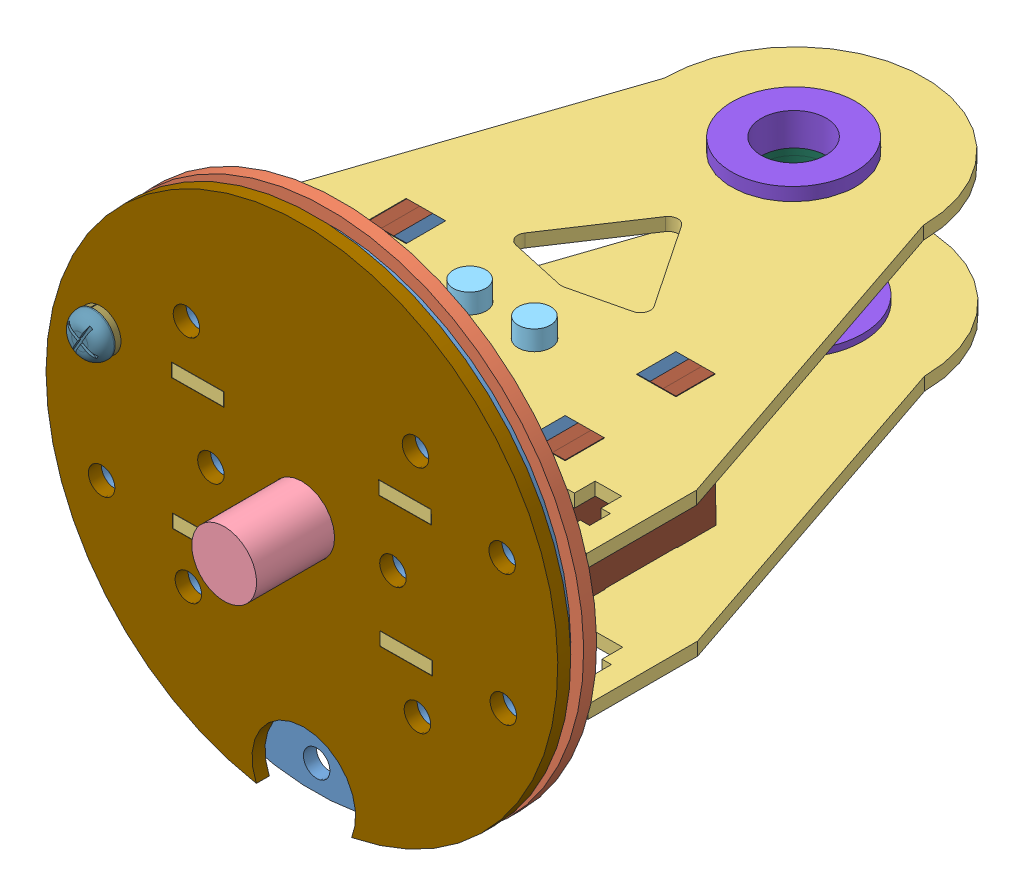
SolidWorks assembly j1, configuration 默认. Lengths in mm.
Overall size (79.65 78.96 105).
36 component instances, 15 part files, 29 mates.
Components (placement in the parent):
- 关节盘-中间层-1: 关节盘-中间层 [默认] at (6.907 71.2488 34.9133) x (0.999966 0.008302 0) z (0 0 1) size (75 75 2)
- 关节盘-两侧层-1: 关节盘-两侧层 [默认] at (6.907 71.2488 32.9133) x (0.999966 0.008302 0) z (0 0 1) size (79 78.31 2)
- 垂直板-1: 垂直板 [默认] at (6.79 60.1974 36.0435) x (0.999966 0.008302 0) z (-0.008302 0.999966 0) size (76.1 93 4.1)
- 垂直板-2: 垂直板 [默认] at (6.6231 80.2967 36.0435) x (0.999966 0.008302 0) z (-0.008302 0.999966 0) size (76.1 93 4.1)
- 螺栓M10-18-1: 螺栓M10-18 [默认] at (6.907 71.2488 32.9133) size (17.5 17.5 23.5)
- 光轴柱-1: 光轴柱 [默认] at (-62.2448 52.8493 0) x (0.350441 -0.936585 0) z (0 0 1) size (28.47 15.53 9.86)
  - M5光轴对线用-1: M5光轴对线用 [默认] at (21.8197 71.1318 7.9133) x (0.325138 0.891437 0.315635) z (-0.939462 0.342654 0) size (5 5 28)
  - 铜套5-7-10-1: 铜套5-7-10 [默认] at (13.3646 74.2157 7.9133) x (0.218976 0.600371 0.769158) z (-0.939462 0.342654 0) size (7 7 10)
  - 铜套5-7-4-1: 铜套5-7-4 [默认] at (17.1224 72.8451 7.9133) x (0.338822 0.928955 0.149138) z (-0.939462 0.342654 0) size (7 7 4)
  - 铜套5-7-4-2: 铜套5-7-4 [默认] at (3.97 77.6422 7.9133) x (0.197516 0.541533 -0.817147) z (-0.939462 0.342654 0) size (7 7 4)
- 法兰轴承10-19-5-金鑫莱-1_6-1: 法兰轴承10-19-5-金鑫莱-1_6 [默认] at (6.8319 80.2985 -37.0867) x (0.526763 0.004373 0.850001) z (-0.008302 0.999966 0) size (21 21 5)
- 法兰轴承10-19-5-金鑫莱-1_6-2: 法兰轴承10-19-5-金鑫莱-1_6 [默认] at (6.9822 62.1991 -37.0867) x (0.500266 0.004153 0.865862) z (0.008302 -0.999966 0) size (21 21 5)
- 关节盘-两侧层-m4孔-1: 关节盘-两侧层-m4孔 [默认] at (6.907 71.2488 36.9133) x (0.999966 0.008302 0) z (0 0 1) size (79 78.31 2)
- 线口板-2: 线口板 [默认] at (-86.2629 82.2299 14.3053) x (-0.036209 -0.999344 0) z (0 0 1) size (22.35 6.98 23.1)
  - 线口板-1: 线口板 [默认] at (-3.3196 112.811 -12.4421) x (0 0 1) z (0.044504 -0.999009 0) size (23.1 22.1 2)
  - 线口板-M4孔-1: 线口板-M4孔 [默认] at (-3.4086 114.809 -12.4421) x (0 0 1) z (0.044504 -0.999009 0) size (23.1 22.1 2)
  - 线口板-M4孔-2: 线口板-M4孔 [默认] at (-3.4976 116.807 -12.4421) x (0 0 1) z (0.044504 -0.999009 0) size (23.1 22.1 2)
- 线口板-3: 线口板 [默认] at (99.8818 83.7753 6.5212) x (0.052796 -0.998605 0) z (0 0 -1) size (22.35 6.98 23.1)
  - 线口板-1: 线口板 [默认] at (-3.3196 112.811 -12.4421) x (0 0 1) z (0.044504 -0.999009 0) size (23.1 22.1 2)
  - 线口板-M4孔-1: 线口板-M4孔 [默认] at (-3.4086 114.809 -12.4421) x (0 0 1) z (0.044504 -0.999009 0) size (23.1 22.1 2)
  - 线口板-M4孔-2: 线口板-M4孔 [默认] at (-3.4976 116.807 -12.4421) x (0 0 1) z (0.044504 -0.999009 0) size (23.1 22.1 2)
- 光轴柱-2: 光轴柱 [默认] at (-72.2445 52.7663 0) x (0.350441 -0.936585 0) z (0 0 1) size (28.47 15.53 9.86)
  - M5光轴对线用-1: M5光轴对线用 [默认] at (21.8197 71.1318 7.9133) x (0.325138 0.891437 0.315635) z (-0.939462 0.342654 0) size (5 5 28)
  - 铜套5-7-10-1: 铜套5-7-10 [默认] at (13.3646 74.2157 7.9133) x (0.218976 0.600371 0.769158) z (-0.939462 0.342654 0) size (7 7 10)
  - 铜套5-7-4-1: 铜套5-7-4 [默认] at (17.1224 72.8451 7.9133) x (0.338822 0.928955 0.149138) z (-0.939462 0.342654 0) size (7 7 4)
  - 铜套5-7-4-2: 铜套5-7-4 [默认] at (3.97 77.6422 7.9133) x (0.197516 0.541533 -0.817147) z (-0.939462 0.342654 0) size (7 7 4)
- M4螺栓螺母垫片16-1: M4螺栓螺母垫片16 [默认] at (-40.0759 -6.7925 45.0566) x (0.498996 -0.866604 0) z (0 0 1) size (8.9 8.9 18.35)
  - M4弹簧垫片-1-6.3-1: M4弹簧垫片-1-6.3 [默认] at (-68.1827 57.608 -5.1433) x (-0.994897 -0.100898 0) z (0 0 -1) size (6.3 6.3 1)
  - 螺母M4-1: 螺母M4 [默认] at (-68.1827 57.608 -16.1433) x (-0.994897 -0.100898 0) z (0 0 -1) size (7.74 6.73 3)
  - 螺栓M4-16-1: 螺栓M4-16 [默认] at (-68.1827 57.608 -5.1433) x (-0.50685 0.862034 0) z (0 0 -1) size (6.5 6.5 18.35)
- M10垫片16-1-1: M10垫片16-1 [默认] at (6.8485 78.2985 -37.0867) x (0.653384 0.005424 0.757007) z (-0.008302 0.999966 0) size (16 16 1)
- M10垫片16-1-2: M10垫片16-1 [默认] at (6.8568 77.2986 -37.0867) x (0.653384 0.005424 0.757007) z (-0.008302 0.999966 0) size (16 16 1)
- M10垫片16-1-3: M10垫片16-1 [默认] at (6.8651 76.2986 -37.0867) x (-0.117982 -0.000979 0.993015) z (-0.008302 0.999966 0) size (16 16 1)
- M10垫片16-1-4: M10垫片16-1 [默认] at (6.9739 63.1991 -37.0867) x (0.214974 0.001785 0.976618) z (-0.008302 0.999966 0) size (16 16 1)
- M10垫片16-1-5: M10垫片16-1 [默认] at (6.9656 64.199 -37.0867) x (0.336961 0.002797 0.941515) z (-0.008302 0.999966 0) size (16 16 1)
- M10垫片16-1-6: M10垫片16-1 [默认] at (6.9573 65.199 -37.0867) x (0.336961 0.002797 0.941515) z (-0.008302 0.999966 0) size (16 16 1)
Mates (geometry in assembly coordinates):
- 重合2: coincident aligned: circle of 关节盘-中间层-1; circle of 关节盘-两侧层-1
- 同心1: concentric aligned: cylinder of 关节盘-中间层-1 through (24.7308 53.7185 36.9133) axis (0 0 -1) radius 2.05; cylinder of 关节盘-两侧层-1 through (24.7308 53.7185 34.9133) axis (0 0 -1) radius 2.05
- 重合10: coincident aligned: circle of 关节盘-两侧层-1; circle of 垂直板-1
- 平行1: parallel anti-aligned: plane of 关节盘-两侧层-1 through (-4.9678 62.1499 34.9133) normal (0.008302 -0.999966 0); plane of 垂直板-1 through (6.9822 62.1991 -37.0867) normal (-0.008302 0.999966 0)
- 重合11: coincident aligned: circle of 关节盘-两侧层-1; circle of 垂直板-2
- 同心8: concentric aligned: circle of 关节盘-两侧层-1; circle of 螺栓M10-18-1
- 重合12: coincident aligned: plane of 关节盘-两侧层-1 through (7.0551 53.4184 32.9133) normal (0 0 -1); circle of 螺栓M10-18-1
- 平行2: parallel aligned: plane of 垂直板-1 through (6.9822 62.1991 -37.0867) normal (-0.008302 0.999966 0); plane of 垂直板-2 through (6.8153 82.2984 -37.0867) normal (-0.008302 0.999966 0)
- 同心36: concentric aligned: cylinder of 垂直板-2 through (6.8153 82.2984 -37.0867) axis (0.008302 -0.999966 0) radius 9.55; cylinder of 法兰轴承10-19-5-金鑫莱-1_6-1 through (6.7987 84.2983 -37.0867) axis (0.008302 -0.999966 0) radius 9.5
- 重合66: coincident anti-aligned: plane of 垂直板-2 through (6.8319 80.2985 -37.0867) normal (0.008302 -0.999966 0); plane of 法兰轴承10-19-5-金鑫莱-1_6-1 through (6.8319 80.2985 -37.0867) normal (-0.008302 0.999966 0)
- 同心35: concentric anti-aligned: cylinder of 垂直板-1 through (6.9822 62.1991 -37.0867) axis (0.008302 -0.999966 0) radius 9.55; cylinder of 法兰轴承10-19-5-金鑫莱-1_6-2 through (7.0154 58.1992 -37.0867) axis (-0.008302 0.999966 0) radius 9.5
- 重合65: coincident anti-aligned: plane of 垂直板-1 through (6.9822 62.1991 -37.0867) normal (-0.008302 0.999966 0); plane of 法兰轴承10-19-5-金鑫莱-1_6-2 through (6.9822 62.1991 -37.0867) normal (0.008302 -0.999966 0)
- 重合74: coincident aligned: circle of 关节盘-中间层-1; circle of 关节盘-两侧层-m4孔-1
- 重合75: coincident aligned: circle of 关节盘-中间层-1; circle of 关节盘-两侧层-m4孔-1
- 重合82: coincident anti-aligned: plane of 垂直板-2 through (6.8319 80.2985 -37.0867) normal (0.008302 -0.999966 0); plane of 光轴柱-1/铜套5-7-4-2 through (11.8317 80.34 7.9133) normal (-0.008302 0.999966 0)
- 同心38: concentric aligned: cylinder of 垂直板-2 through (11.8151 82.3399 7.9133) axis (0.008302 -0.999966 0) radius 2.55; cylinder of 光轴柱-1/M5光轴对线用-1 through (11.7902 85.3398 7.9133) axis (0.008302 -0.999966 0) radius 2.5
- 同心39: concentric aligned: cylinder of 垂直板-2 through (1.8155 82.2569 7.9133) axis (0.008302 -0.999966 0) radius 2.55; cylinder of 光轴柱-2/M5光轴对线用-1 through (1.7906 85.2568 7.9133) axis (0.008302 -0.999966 0) radius 2.5
- 重合83: coincident anti-aligned: plane of 垂直板-2 through (6.8319 80.2985 -37.0867) normal (0.008302 -0.999966 0); plane of 光轴柱-2/铜套5-7-4-2 through (1.8321 80.257 7.9133) normal (-0.008302 0.999966 0)
- 重合84: coincident anti-aligned: circle of 关节盘-两侧层-m4孔-1; circle of M4螺栓螺母垫片16-1/M4弹簧垫片-1-6.3-1
- 重合85: coincident aligned: circle of M10垫片16-1-1; circle of M10垫片16-1-2
- 重合86: coincident aligned: circle of M10垫片16-1-2; circle of M10垫片16-1-3
- 重合87: coincident anti-aligned: circle of 法兰轴承10-19-5-金鑫莱-1_6-1; circle of M10垫片16-1-1
- 重合88: coincident aligned: circle of M10垫片16-1-5; circle of M10垫片16-1-6
- 重合89: coincident aligned: circle of M10垫片16-1-4; circle of M10垫片16-1-5
- 重合90: coincident aligned: circle of 法兰轴承10-19-5-金鑫莱-1_6-2; circle of M10垫片16-1-4
- 重合91: coincident anti-aligned: line of 垂直板-1 through (30.8693 60.3973 -1.1367) axis (-0.999966 -0.008302 0); line of 线口板-2/线口板-1 through (24.7695 60.3467 -1.1367) axis (0.999966 0.008302 0)
- 重合92: coincident aligned: line of 垂直板-1 through (24.7695 60.3467 -1.1367) axis (0 0 1); line of 线口板-2/线口板-1 through (24.7695 60.3467 -1.1367) axis (0 0 1)
- 重合93: coincident aligned: line of 垂直板-1 through (-10.772 60.0516 -1.1367) axis (-0.999966 -0.008302 0); line of 线口板-3/线口板-1 through (-10.772 60.0516 -1.1367) axis (-0.999966 -0.008302 0)
- 重合94: coincident anti-aligned: line of 垂直板-1 through (-10.772 60.0516 4.9633) axis (0 0 -1); line of 线口板-3/线口板-1 through (-10.772 60.0516 -1.1367) axis (0 0 1)
